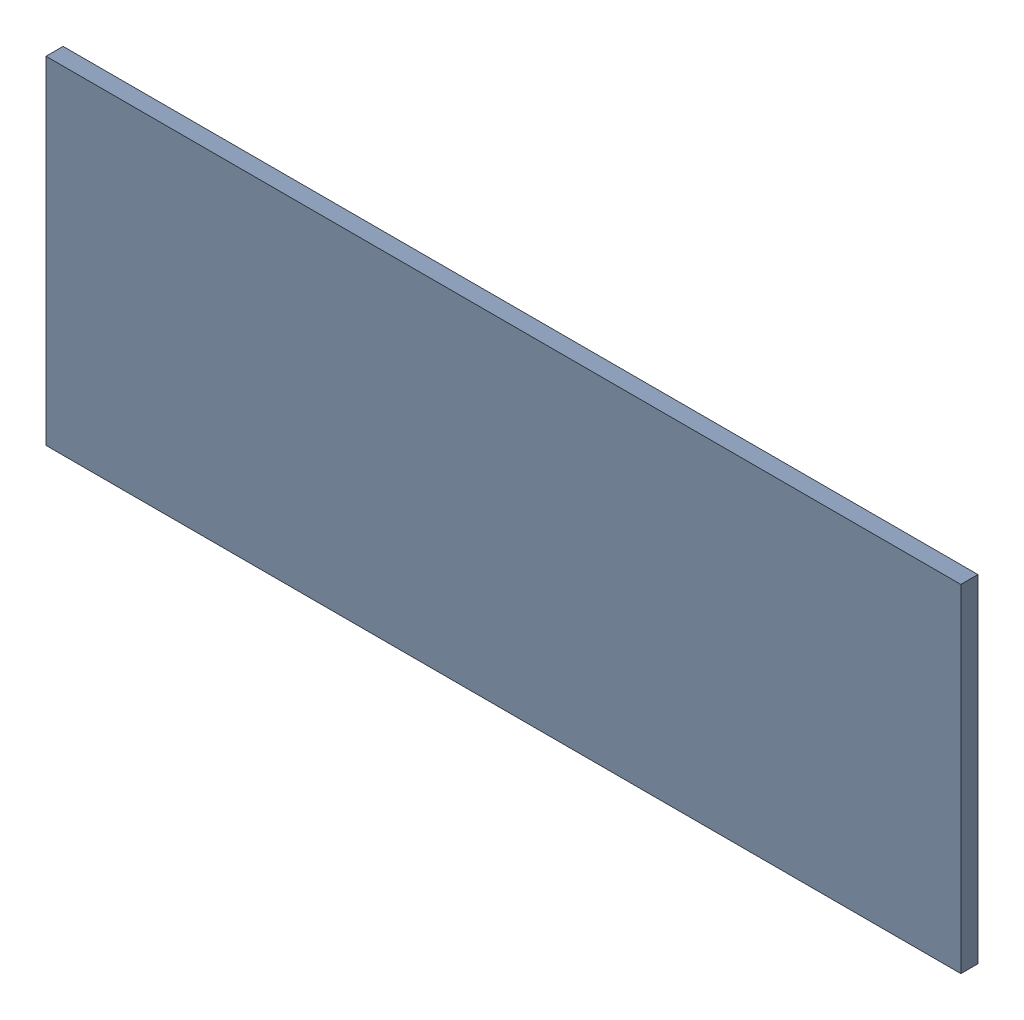
SolidWorks assembly Pad RAK4600-1(14.5mm,27.5mm) on Top Layer, configuration Predeterminado. Lengths in mm.
Overall size (1.9 0.7 0.04).
2 component instances, 1 part files, 0 mates.
Components (placement in the parent):
- Pad RAK4600-1(14.5mm,27.5mm) on Top Layer-1-1: Pad RAK4600-1(14.5mm,27.5mm) on Top Layer-1 [Predeterminado] at (-68.317 -44.187 -0.0457) size (1.9 0.7 0.04)
  - Pad RAK4600-1(14.5mm,27.5mm) on Top Layer-Part-1-1: Pad RAK4600-1(14.5mm,27.5mm) on Top Layer-Part-1 [Predeterminado] at origin size (1.9 0.7 0.04)
